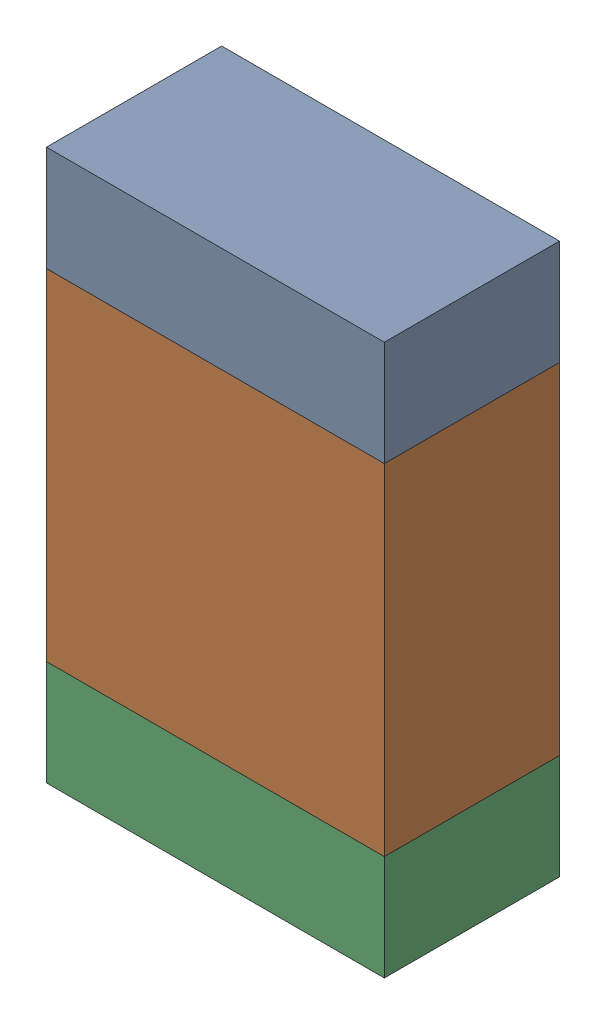
SolidWorks assembly R14-2, configuration Default. Lengths in mm.
Overall size (1.35 2.2 0.7).
6 component instances, 2 part files, 0 mates.
Components (placement in the parent):
- 959207304-2-1: 959207304-2 [Default] at (110.6132 93.495 0) size (1.35 0.42 0.7)
  - Extruded-70-1: Extruded-70 [Default] at origin size (1.35 0.42 0.7)
- 959207440-2-1: 959207440-2 [Default] at (110.6132 92.605 0) size (1.35 1.36 0.7)
  - Extruded-71-1: Extruded-71 [Default] at origin size (1.35 1.36 0.7)
- 959207304-2-2: 959207304-2 [Default] at (110.6132 91.715 0) size (1.35 0.42 0.7)
  - Extruded-70-1: Extruded-70 [Default] at origin size (1.35 0.42 0.7)
